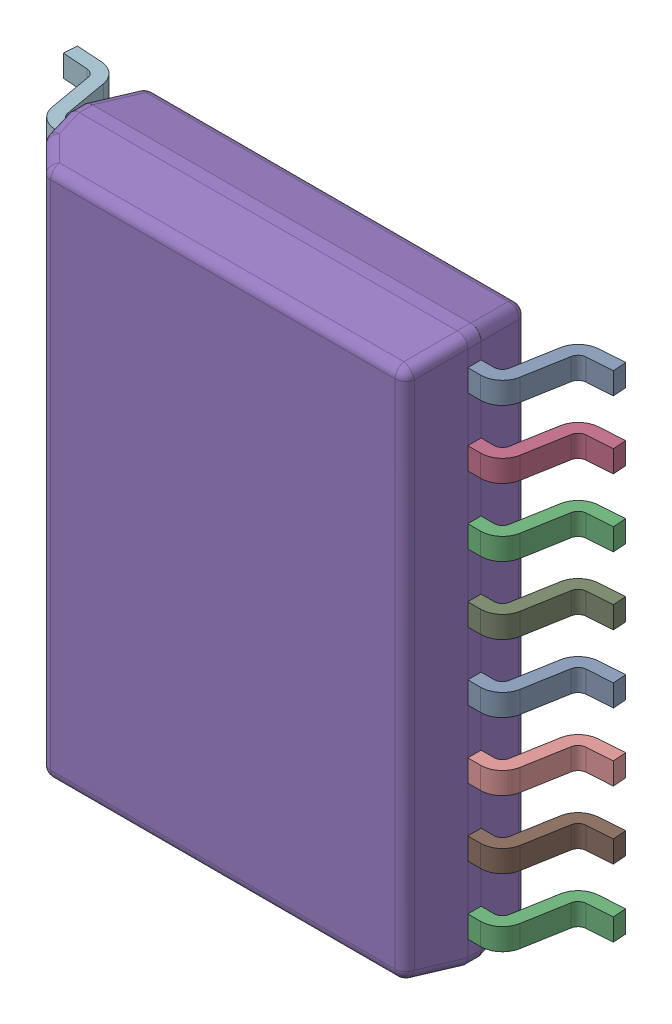
SolidWorks assembly IC6, configuration По умолчанию. Lengths in mm.
Overall size (10.33 10.3 2.59).
18 component instances, 2 part files, 0 mates.
Components (placement in the parent):
- DW0016B_ASM-1: DW0016B_ASM [По умолчанию] at origin size (10.33 10.3 2.59)
  - DW0016B_ASM-Part-1-1: DW0016B_ASM-Part-1 [По умолчанию] at (4.315 -0.635 0.25) x (0 1 0) z (1 0 0) size (0.41 1.57 1.42)
  - DW0016B_ASM-Part-1-2: DW0016B_ASM-Part-1 [По умолчанию] at (-4.315 -1.905 0.25) x (0 -1 0) z (-1 0 0) size (0.41 1.57 1.42)
  - DW0016B_ASM-Part-1-3: DW0016B_ASM-Part-1 [По умолчанию] at (4.315 -4.445 0.25) x (0 1 0) z (1 0 0) size (0.41 1.57 1.42)
  - DW0016B_ASM-Part-1-4: DW0016B_ASM-Part-1 [По умолчанию] at (4.315 3.175 0.25) x (0 1 0) z (1 0 0) size (0.41 1.57 1.42)
  - DW0016B_ASM-Part-1-5: DW0016B_ASM-Part-1 [По умолчанию] at (-4.315 0.635 0.25) x (0 -1 0) z (-1 0 0) size (0.41 1.57 1.42)
  - DW0016B_ASM-Part-1-6: DW0016B_ASM-Part-1 [По умолчанию] at (-4.315 -3.175 0.25) x (0 -1 0) z (-1 0 0) size (0.41 1.57 1.42)
  - DW0016B_ASM-Part-1-7: DW0016B_ASM-Part-1 [По умолчанию] at (-4.315 -4.445 0.25) x (0 -1 0) z (-1 0 0) size (0.41 1.57 1.42)
  - DW0016B_ASM-Part-1-8: DW0016B_ASM-Part-1 [По умолчанию] at (-4.315 3.175 0.25) x (0 -1 0) z (-1 0 0) size (0.41 1.57 1.42)
  - DW0016B_ASM-Part-1-9: DW0016B_ASM-Part-1 [По умолчанию] at (4.315 0.635 0.25) x (0 1 0) z (1 0 0) size (0.41 1.57 1.42)
  - DW0016B_ASM-Part-1-10: DW0016B_ASM-Part-1 [По умолчанию] at (4.315 -1.905 0.25) x (0 1 0) z (1 0 0) size (0.41 1.57 1.42)
  - DW0016B_ASM-Part-1-11: DW0016B_ASM-Part-1 [По умолчанию] at (4.315 -3.175 0.25) x (0 1 0) z (1 0 0) size (0.41 1.57 1.42)
  - DW0016B_ASM-Part-1-12: DW0016B_ASM-Part-1 [По умолчанию] at (-4.315 4.445 0.25) x (0 -1 0) z (-1 0 0) size (0.41 1.57 1.42)
  - DW0016B_ASM-Part-1-13: DW0016B_ASM-Part-1 [По умолчанию] at (4.315 4.445 0.25) x (0 1 0) z (1 0 0) size (0.41 1.57 1.42)
  - DW0016B_ASM-Part-1-14: DW0016B_ASM-Part-1 [По умолчанию] at (-4.315 1.905 0.25) x (0 -1 0) z (-1 0 0) size (0.41 1.57 1.42)
  - DW0016B_ASM-Part-1-15: DW0016B_ASM-Part-1 [По умолчанию] at (4.315 1.905 0.25) x (0 1 0) z (1 0 0) size (0.41 1.57 1.42)
  - DW0016B_ASM-Part-1-16: DW0016B_ASM-Part-1 [По умолчанию] at (-4.315 -0.635 0.25) x (0 -1 0) z (-1 0 0) size (0.41 1.57 1.42)
  - DW0016B_ASM-Part-2-1: DW0016B_ASM-Part-2 [По умолчанию] at (0 0 1.568) x (0 1 0) z (1 0 0) size (10.3 2.29 7.5)
